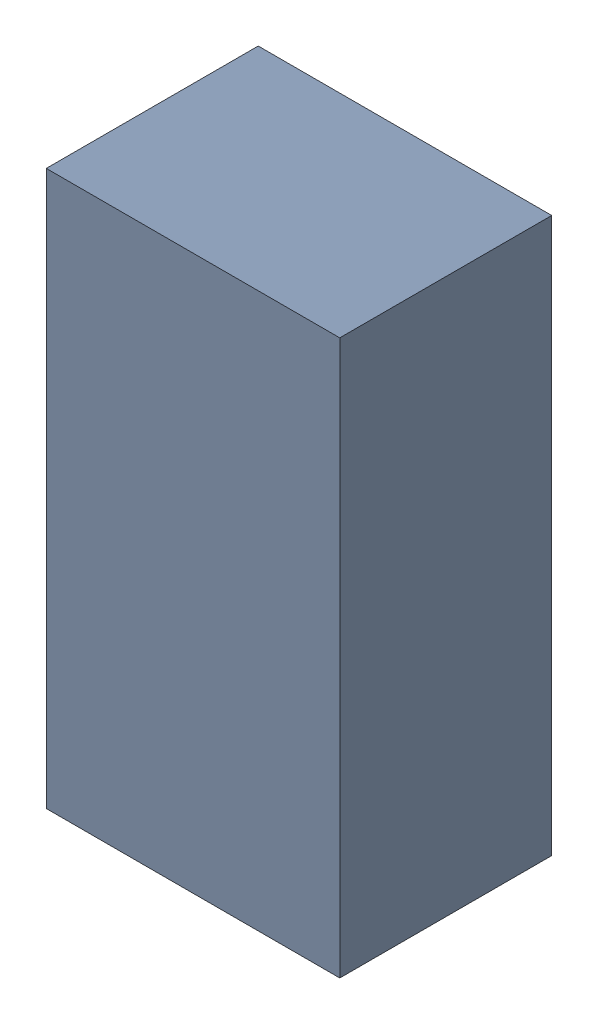
SolidWorks assembly C4, configuration Default. Lengths in mm.
Overall size (1.8 3.4 1.3).
2 component instances, 1 part files, 0 mates.
Components (placement in the parent):
- 5920131968-1: 5920131968 [Default] at (17 42.5 0) size (1.8 3.4 1.3)
  - Extruded_2-1: Extruded_2 [Default] at origin size (1.8 3.4 1.3)
